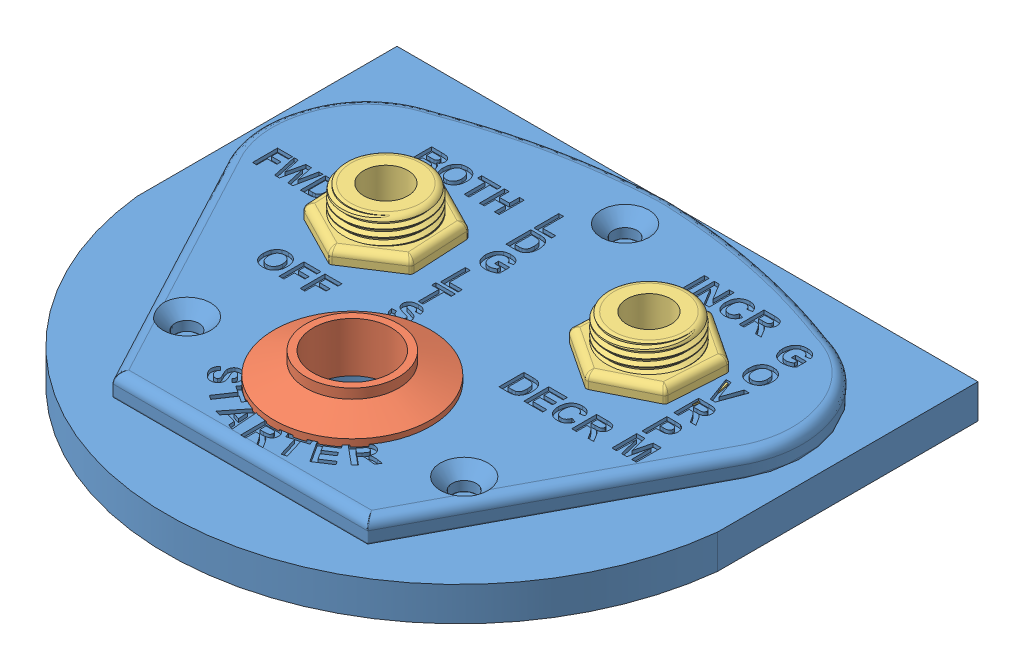
SolidWorks assembly panel_with_letters, configuration По умолчанию. Lengths in mm.
Overall size (86.24 13.72 75.65).
4 component instances, 3 part files, 5 mates.
Components (placement in the parent):
- 206h_sw_box_cover_w_letters_206h02b-1: 206h_sw_box_cover_w_letters_206h02b [По умолчанию] at origin size (86.24 11.85 75.65)
- 206h_sw_starter_btn_cover_206h04-1: 206h_sw_starter_btn_cover_206h04 [По умолчанию] at (0 -0.2382 23.8517) x (0.801335 0 -0.598216) z (0.598216 0 0.801335) size (26 7 26)
- 206h_6mm_gov_switch_adapter_206h05-1: 206h_6mm_gov_switch_adapter_206h05 [По умолчанию] at (17.8813 0 0) x (0.869205 0 -0.494452) z (0.494452 0 0.869205) size (17.8 8.72 17.8)
- 206h_6mm_gov_switch_adapter_206h05-2: 206h_6mm_gov_switch_adapter_206h05 [По умолчанию] at (-16.2693 0 2.8597) x (0.914421 0 0.404765) z (-0.404765 0 0.914421) size (17.8 8.72 17.8)
Mates (geometry in assembly coordinates):
- Concentric1: concentric anti-aligned: cylinder of 206h_sw_box_cover_w_letters_206h02b-1 through (0 -2 23.8517) axis (0 1 0) radius 7; cylinder of 206h_sw_starter_btn_cover_206h04-1 through (0 2.7618 23.8517) axis (0 -1 0) radius 5.5
- Concentric2: concentric aligned: cylinder of 206h_sw_box_cover_w_letters_206h02b-1 through (17.8813 0.1 0) axis (0 -1 0) radius 6.1; cylinder of 206h_6mm_gov_switch_adapter_206h05-1 through (17.8813 8.5 0) axis (0 -1 0) radius 3.1
- Coincident1: coincident anti-aligned: plane of 206h_sw_box_cover_w_letters_206h02b-1 through (-28.8204 3 19.1493) normal (0 1 0); plane of 206h_6mm_gov_switch_adapter_206h05-1 through (17.8813 3 0) normal (0 -1 0)
- Concentric3: concentric aligned: cylinder of 206h_sw_box_cover_w_letters_206h02b-1 through (-16.2693 0.1 2.8597) axis (0 -1 0) radius 6.1; cylinder of 206h_6mm_gov_switch_adapter_206h05-2 through (-16.2693 8.5 2.8597) axis (0 -1 0) radius 3.1
- Coincident2: coincident anti-aligned: plane of 206h_sw_box_cover_w_letters_206h02b-1 through (-28.8204 3 19.1493) normal (0 1 0); plane of 206h_6mm_gov_switch_adapter_206h05-2 through (-16.2693 3 2.8597) normal (0 -1 0)
